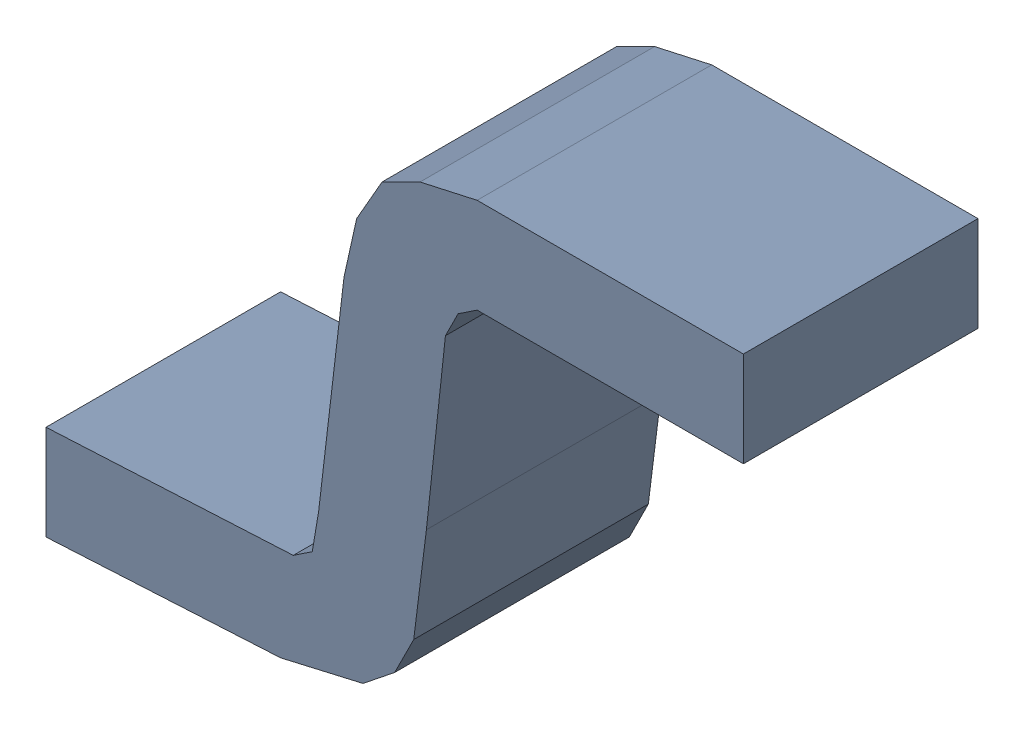
SolidWorks assembly SW3dPS-LQFP32_PINLQFP-33, configuration Default. Lengths in mm.
Overall size (1.1 0.8 0.37).
4 component instances, 2 part files, 0 mates.
Components (placement in the parent):
- SW3dPS-LQFP32_Free-Models3-1: SW3dPS-LQFP32_Free-Models3 [Default] at origin size (1.1 0.8 0.37)
  - SW3dPS-LQFP32_450941905-1: SW3dPS-LQFP32_450941905 [Default] at (-0.54 -0.325 -0.3573) size (1.1 0.8 0.37)
    - SW3dPS-LQFP32_Extruded15-1: SW3dPS-LQFP32_Extruded15 [Default] at origin size (1.1 0.8 0.37)
- SW3dPS-LQFP32_Board2-1: SW3dPS-LQFP32_Board2 [Default] at (0 0 -0.0938) size (0.01 0.01 0.11)
